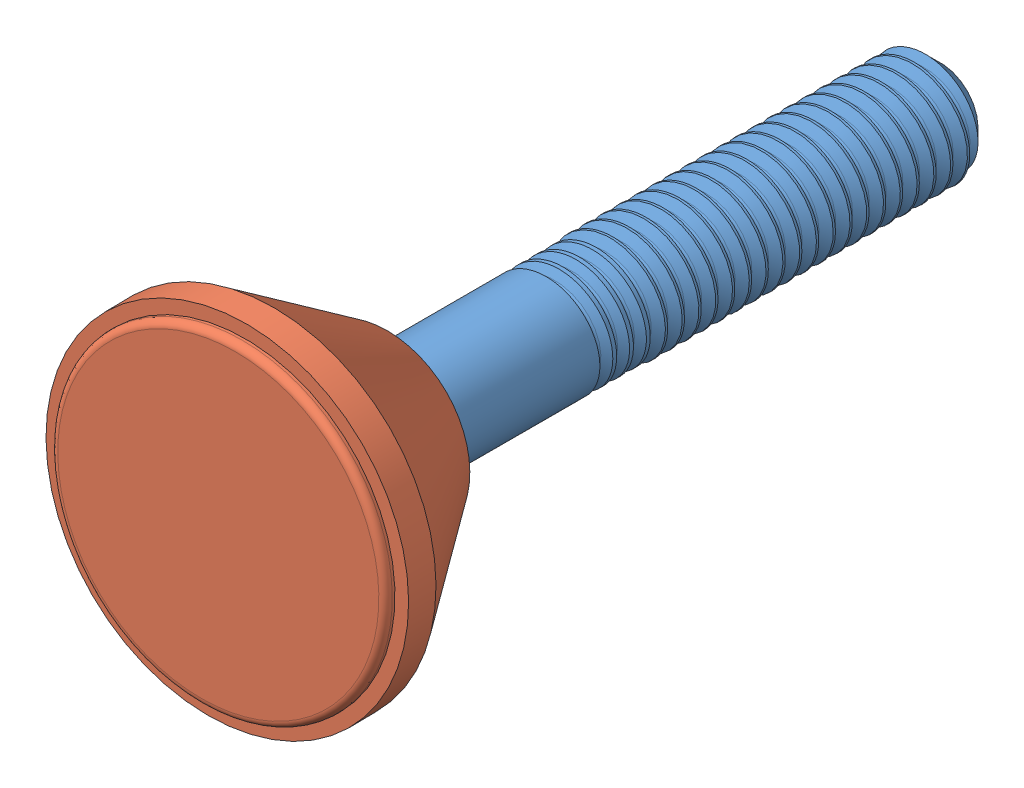
SolidWorks assembly foot_full, configuration Default. Lengths in mm.
Overall size (36.39 36.22 55.51).
2 component instances, 2 part files, 1 mates.
Components (placement in the parent):
- ball-1: ball [Default] at (27.546 33.7465 53.377) size (12 12 51.43)
- foot-1: foot [Default] at (27.546 33.7465 53.377) x (-0.788359 -0.60973 0.081969) z (0.611816 -0.791 0.000417) size (25.4 12.73 25.4)
Mates (geometry in assembly coordinates):
- Concentric1: concentric: sphere of ball-1; sphere of foot-1
